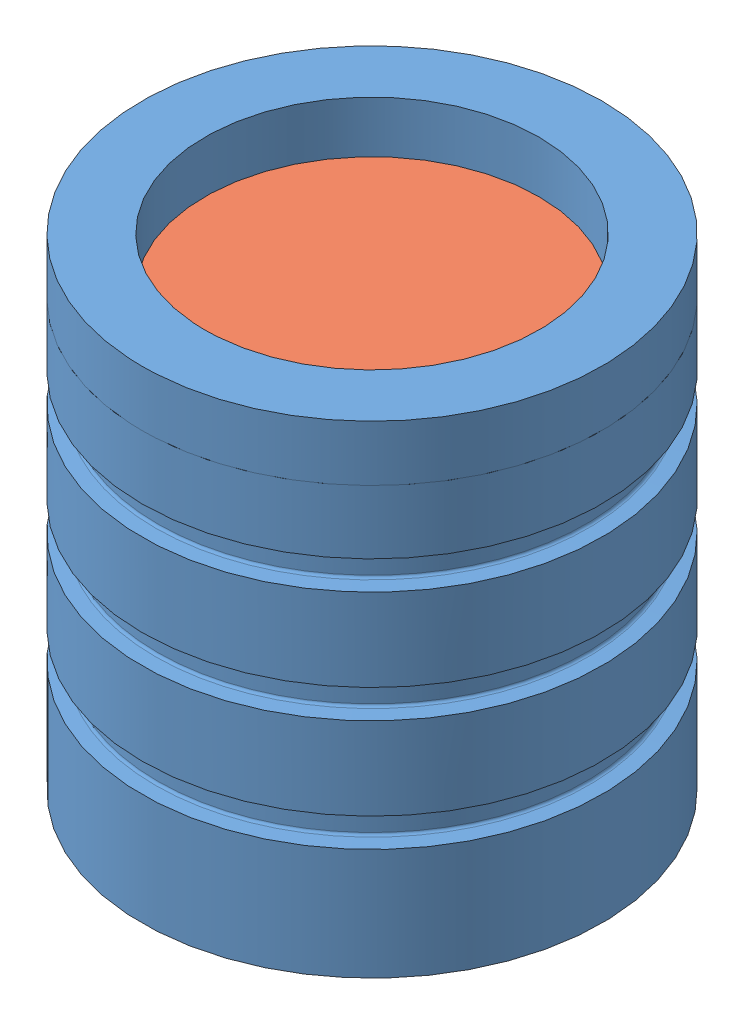
SolidWorks assembly NozzleFlowAssem, configuration Default. Lengths in mm.
Overall size (82.55 86.59 82.55).
2 component instances, 2 part files, 0 mates.
Components (placement in the parent):
- Nozzle_Flow-1: Nozzle_Flow [Default] at (-35.9152 -16.1547 3.9099) size (82.55 86.59 82.55)
- LID1-1: LID1 [Default] at origin size (61.71 0.74 61.71)
